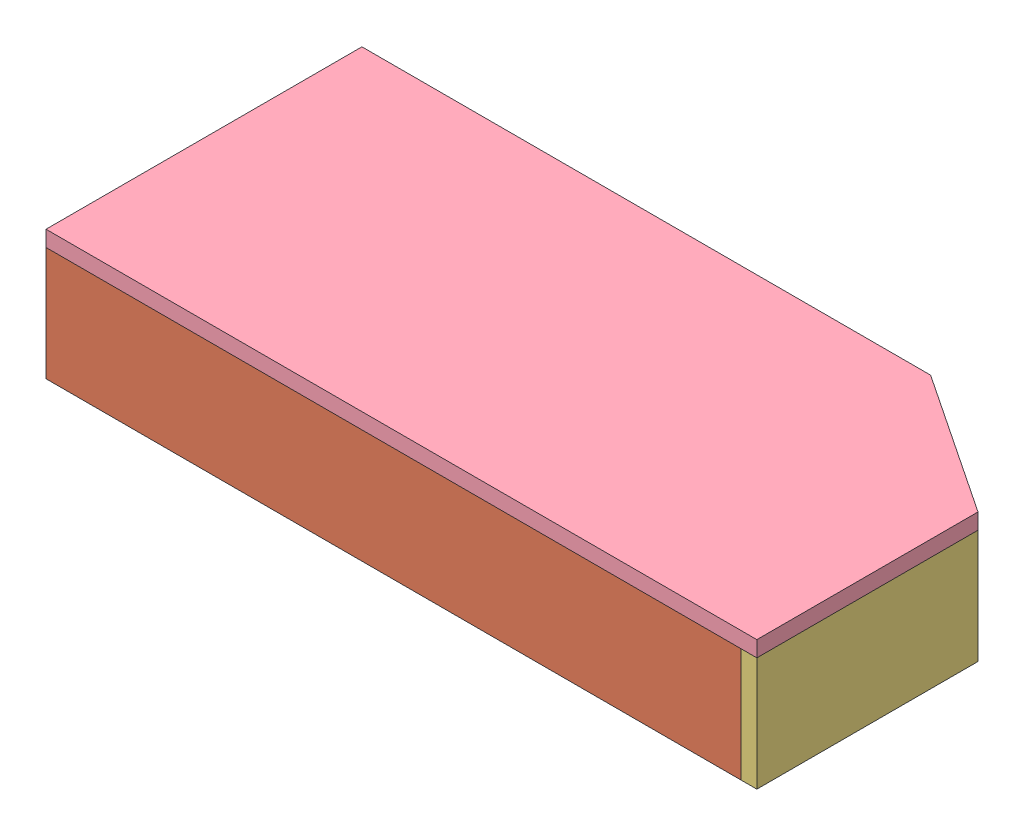
SolidWorks assembly BatteryCaseRAssem, configuration Default. Lengths in mm.
Overall size (142.88 26.04 63.5).
6 component instances, 6 part files, 9 mates.
Components (placement in the parent):
- BatteryCaseShort-1: BatteryCaseShort [Default] at (-92.8619 -9.4041 55.3909) size (114.3 22.86 3.17)
- BatteryCaseLong-1: BatteryCaseLong [Default] at (-80.1619 -9.4041 115.7159) size (139.7 22.86 3.17)
- BatteryCaseEnd-1: BatteryCaseEnd [Default] at (-8.7244 -9.4041 95.0784) x (0 0 1) z (0 -1 0) size (44.45 3.17 22.86)
- Part7^BatteryCaseRAssem-1: Part7^BatteryCaseRAssem [Default] at origin (virtual)
- Part8^BatteryCaseRAssem-1: Part8^BatteryCaseRAssem [Default] at origin (virtual)
- Part9-1: Part9 [Default] at (0 3.6134 0) x (1 0 0) z (0 1 0) size (142.88 63.5 3.17)
Mates (geometry in assembly coordinates):
- Coincident1: coincident anti-aligned: plane of BatteryCaseLong-1 through (-10.3119 -20.8341 117.3034) normal (1 0 0); plane of BatteryCaseEnd-1 through (-10.3119 -9.4041 95.0784) normal (-1 0 0)
- Coincident2: coincident aligned: plane of BatteryCaseLong-1 through (-80.1619 -9.4041 117.3034) normal (0 0 1); plane of BatteryCaseEnd-1 through (-10.3119 -20.8341 117.3034) normal (0 0 1)
- Coincident4: coincident aligned: plane of BatteryCaseLong-1 through (-150.0119 2.0259 117.3034) normal (0 1 0); plane of BatteryCaseEnd-1 through (-10.3119 2.0259 72.8534) normal (0 1 0)
- Coincident5: coincident aligned: plane of BatteryCaseShort-1 through (-150.0119 -20.8341 56.9784) normal (-1 0 0); plane of BatteryCaseLong-1 through (-150.0119 -20.8341 117.3034) normal (-1 0 0)
- Coincident7: coincident aligned: plane of BatteryCaseShort-1 through (-150.0119 2.0259 56.9784) normal (0 1 0); plane of BatteryCaseEnd-1 through (-10.3119 2.0259 72.8534) normal (0 1 0)
- Distance1: distance = 63.5 mm anti-aligned: plane of BatteryCaseLong-1 through (-80.1619 -9.4041 117.3034) normal (0 0 1); plane of BatteryCaseShort-1 through (-92.8619 -9.4041 53.8034) normal (0 0 -1)
- Coincident13: coincident anti-aligned: plane of BatteryCaseShort-1 through (-150.0119 2.0259 56.9784) normal (0 1 0); plane of Part9-1 through (0 2.0259 0) normal (0 -1 0)
- Coincident14: coincident aligned: plane of BatteryCaseEnd-1 through (-7.1369 -9.4041 95.0784) normal (1 0 0); plane of Part9-1 through (-7.1369 5.2009 117.3034) normal (1 0 0)
- Coincident15: coincident aligned: plane of BatteryCaseLong-1 through (-80.1619 -9.4041 117.3034) normal (0 0 1); plane of Part9-1 through (-150.0119 5.2009 117.3034) normal (0 0 1)
